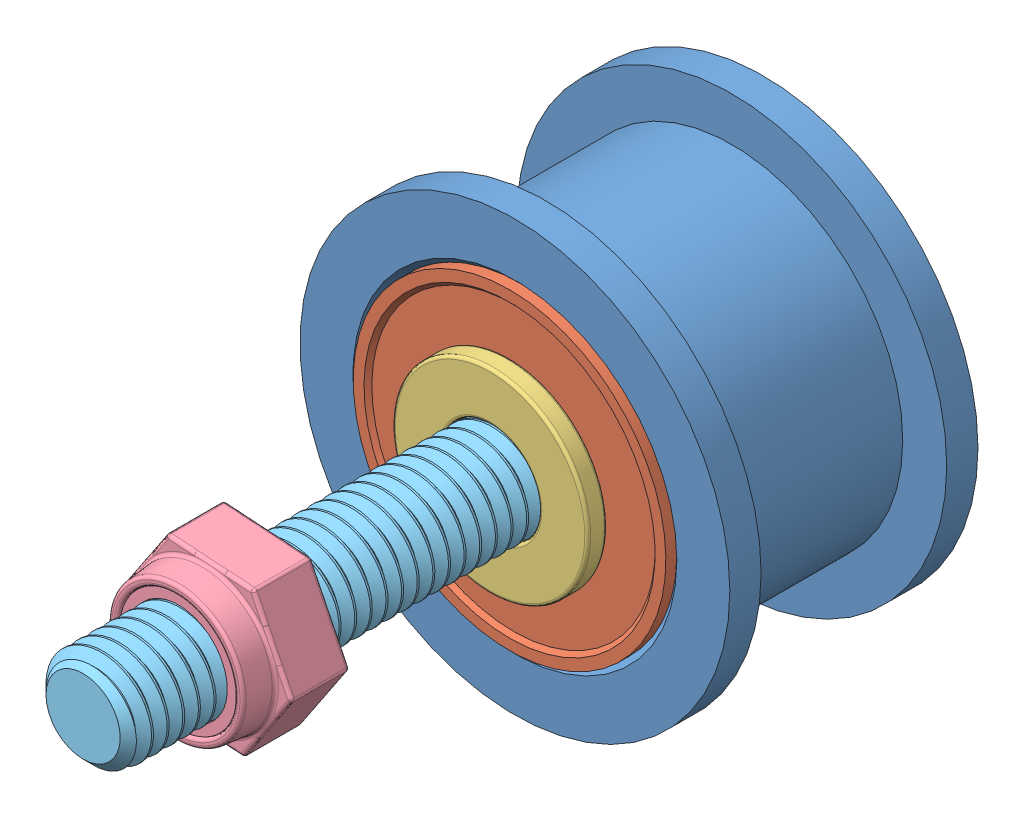
SolidWorks assembly Idler Wheel Assembly, configuration Default. Lengths in mm.
Overall size (22.45 22.45 38.28).
7 component instances, 6 part files, 11 mates.
Components (placement in the parent):
- V-Slot Idler Pulley-1: V-Slot Idler Pulley [Default] at (8.0419 11.7957 16.7627) size (22 22 12.7)
- Precision Ball Bearing-1: Precision Ball Bearing [Default] at (8.0419 11.7957 20.8877) x (0 0 1) z (-0.613966 -0.789332 0) size (5 16 16)
- Precision Ball Bearing-2: Precision Ball Bearing [Default] at (8.0419 11.7957 12.7127) x (0 0 1) z (-1 0 0) size (5 16 16)
- 5mm Precision Washer-1: 5mm Precision Washer [Default] at (8.0419 11.7957 23.3877) x (0 0 1) z (-0.948012 0.318234 0) size (1 10 10)
- Nylon Insert Hex Locknut 5mm-1: Nylon Insert Hex Locknut 5mm [Default] at (8.0419 11.7957 35.9756) x (-0.065614 -0.997845 0) z (0 0 1) size (7.68 8.82 4.5)
- 5mmX35mm_Buttonhead(McMaster_92095A220)-1: 5mmX35mm_Buttonhead(McMaster_92095A220) [92095A220] at (8.0419 11.7957 7.4627) x (-1 0 0) z (0 0 -1) size (9.5 9.5 38.28)
- .125 Inch Aluminum Spacer-1: .125 Inch Aluminum Spacer [Default] at (8.0419 11.7957 15.2127) x (0 0 1) z (-0.99922 -0.039494 0) size (3.17 8 8)
Mates (geometry in assembly coordinates):
- Concentric1: concentric anti-aligned: cylinder of V-Slot Idler Pulley-1 through (8.0419 11.7957 16.7627) axis (0 0 1) radius 7.9875; cylinder of Precision Ball Bearing-1 through (8.0419 11.7957 23.3877) axis (0 0 -1) radius 8
- Concentric2: concentric anti-aligned: cylinder of Precision Ball Bearing-1 through (8.0419 11.7957 18.3877) axis (0 0 1) radius 2.5; cylinder of 5mm Precision Washer-1 through (8.0419 11.7957 24.3877) axis (0 0 -1) radius 2.5
- Coincident3: coincident anti-aligned: plane of V-Slot Idler Pulley-1 through (8.0419 19.7832 15.2127) normal (0 0 -1); plane of Precision Ball Bearing-2 through (8.0419 11.7957 15.2127) normal (0 0 1)
- Concentric3: concentric anti-aligned: cylinder of V-Slot Idler Pulley-1 through (8.0419 11.7957 16.7627) axis (0 0 1) radius 7.9875; cylinder of Precision Ball Bearing-2 through (8.0419 11.7957 15.2127) axis (0 0 -1) radius 8
- Coincident4: coincident anti-aligned: plane of Precision Ball Bearing-2 through (8.0419 11.7957 10.2127) normal (0 0 -1); plane of 5mmX35mm_Buttonhead(McMaster_92095A220)-1 through (8.0419 7.0457 10.2127) normal (0 0 1)
- Concentric4: concentric anti-aligned: cylinder of Precision Ball Bearing-2 through (8.0419 11.7957 10.2127) axis (0 0 1) radius 2.5; cylinder of 5mmX35mm_Buttonhead(McMaster_92095A220)-1 through (8.0419 11.7957 7.4627) axis (0 0 -1) radius 4.75
- Concentric7: concentric anti-aligned: circle of Precision Ball Bearing-1; circle of .125 Inch Aluminum Spacer-1
- Concentric8: concentric aligned: circle of Nylon Insert Hex Locknut 5mm-1; circle of .125 Inch Aluminum Spacer-1
- Coincident5: coincident anti-aligned: plane of Precision Ball Bearing-1 through (8.0419 11.7957 18.3877) normal (0 0 -1); plane of .125 Inch Aluminum Spacer-1 through (8.0419 11.7957 18.3877) normal (0 0 1)
- Coincident7: coincident anti-aligned: plane of Precision Ball Bearing-2 through (8.0419 11.7957 15.2127) normal (0 0 1); plane of .125 Inch Aluminum Spacer-1 through (8.0419 11.7957 15.2127) normal (0 0 -1)
- Coincident8: coincident anti-aligned: plane of Precision Ball Bearing-1 through (8.0419 11.7957 23.3877) normal (0 0 1); plane of 5mm Precision Washer-1 through (8.0419 11.7957 23.3877) normal (0 0 -1)
